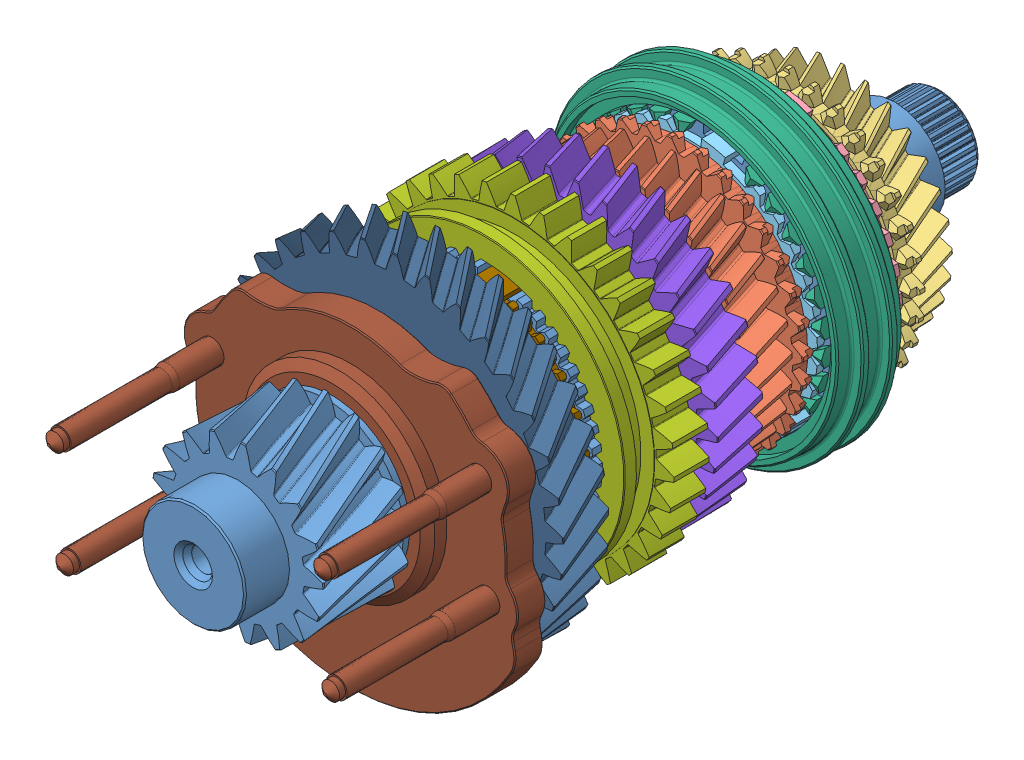
SolidWorks assembly lock3, configuration Default. Lengths in mm.
Overall size (149.64 149.67 253.48).
12 component instances, 11 part files, 28 mates.
Components (placement in the parent):
- Part1 - Copy-1: Part1 - Copy [Default] at (-9.0719 9.4939 -127.4378) size (88.21 88.13 251.48)
- 3rd Gear-1: 3rd Gear [Default] at (-9.0719 9.4939 -34.8178) x (0.981754 -0.190153 0) z (0.190153 0.981754 0) size (89.95 22.5 89.85)
- 4th-1: 4th [Default] at (-9.0719 9.4939 -94.2778) x (1 0 0) z (0 1 0) size (89.95 21.35 89.85)
- 4th Mesh - Copy-1: 4th Mesh - Copy [Default] at (-9.0719 9.4939 -71.9278) x (0.985045 0.172299 0) z (-0.172299 0.985045 0) size (86.29 9.5 85.96)
- gear3 mesh-1: gear3 mesh [Default] at (-9.0719 9.4939 -45.7778) x (0.307677 0.951491 0) z (-0.951491 0.307677 0) size (86.48 9.6 86.41)
- Part3-1: Part3 [Default] at (-9.0719 9.4939 -43.5517) x (0.888761 -0.458371 0) z (-0.458371 -0.888761 0) size (106.2 22 106.2)
- reverse-1: reverse [Default] at (-9.0719 9.4939 16.1439) x (0.555504 -0.831514 0) z (0.831514 0.555504 0) size (107.95 22 107.84)
- 2nd gear-1: 2nd gear [Default] at (-9.0719 9.4939 -1.7178) x (-0.913023 -0.407908 0) z (0.407908 -0.913023 0) size (102.15 21.6 102.2)
- reverse mesh-1: reverse mesh [Default] at (-9.0719 9.4939 4.6222) x (0.487458 -0.873146 0) z (0.873146 0.487458 0) size (80 8.5 80)
- reverse mesh-2: reverse mesh [Default] at (-9.0719 9.4939 32.2222) x (-0.788428 -0.615126 0) z (-0.615126 0.788428 0) size (80 8.5 80)
- 1st gear-1: 1st gear [Default] at (-9.0719 9.4939 41.2222) x (0.996072 -0.088542 0) z (-0.088542 -0.996072 0) size (115.11 23.6 115.04)
- base-1: base [Default] at (-9.0719 9.4939 61.5422) x (-0.996102 -0.088213 0) z (-0.088213 0.996102 0) size (110 64.6 106)
Mates (geometry in assembly coordinates):
- Concentric1: concentric aligned: cylinder of Part1 - Copy-1 through (-9.0719 9.4939 59.5422) axis (0 0 -1) radius 24; cylinder of 3rd Gear-1 through (-9.0719 9.4939 -19.1177) axis (0 0 -1) radius 24
- Lock1: lock: unknown of Part1 - Copy-1; unknown of 3rd Gear-1
- Concentric2: concentric aligned: cylinder of Part1 - Copy-1 through (-9.0719 9.4939 59.5422) axis (0 0 -1) radius 24; cylinder of 4th-1 through (-9.0719 9.4939 -73.0277) axis (0 0 -1) radius 24
- Coincident1: coincident aligned: plane of Part1 - Copy-1 through (-9.0719 9.4939 -94.2778) normal (0 0 -1); plane of 4th-1 through (-9.0719 9.4939 -94.2778) normal (0 0 -1)
- Concentric3: concentric aligned: cylinder of Part1 - Copy-1 through (-9.0719 9.4939 -94.2778) axis (0 0 -1) radius 17; cylinder of 4th Mesh - Copy-1 through (-9.0719 9.4939 -62.4278) axis (0 0 -1) radius 24
- Distance1: distance = 1 mm anti-aligned: plane of 4th Mesh - Copy-1 through (-9.0719 9.4939 -69.2778) normal (0 0 1); plane of Part1 - Copy-1 through (-9.0719 9.4939 -68.2778) normal (0 0 -1)
- Concentric4: concentric aligned: cylinder of Part1 - Copy-1 through (-9.0719 9.4939 59.5422) axis (0 0 -1) radius 24; cylinder of gear3 mesh-1 through (-9.0719 9.4939 -35.7778) axis (0 0 -1) radius 24
- Distance2: distance = 1 mm anti-aligned: plane of gear3 mesh-1 through (-9.0719 9.4939 -45.7778) normal (0 0 -1); plane of Part1 - Copy-1 through (-9.0719 9.4939 -46.7778) normal (0 0 1)
- Concentric5: concentric anti-aligned: cylinder of Part1 - Copy-1 through (-9.0719 9.4939 59.5422) axis (0 0 -1) radius 24; cylinder of Part3-1 through (-9.0719 9.4939 -188.902) axis (0 0 1) radius 44.115
- Parallel1: parallel anti-aligned: plane of Part1 - Copy-1 through (10.643 45.5071 -68.2778) normal (-0.483639 0.875268 0); plane of Part3-1 through (13.7756 47.2314 -36.7966) normal (0.483639 -0.875268 0)
- Concentric6: concentric aligned: cylinder of Part1 - Copy-1 through (-9.0719 9.4939 59.5422) axis (0 0 -1) radius 24; cylinder of reverse-1 through (-9.0719 9.4939 26.1439) axis (0 0 -1) radius 40
- LimitAngle1: limit planar angle = 0.083619 rad aligned: line of 4th Mesh - Copy-1 through (25.78 -16.2142 -71.9278) axis (-0.804751 0.593613 0); line of Part1 - Copy-1 through (28.4032 -13.5815 -68.2778) axis (-0.851518 0.524325 0)
- LimitAngle2: limit planar angle = 0.068648 rad aligned: line of gear3 mesh-1 through (23.9988 -14.1441 -43.1178) axis (0.813547 -0.581499 0); line of Part1 - Copy-1 through (25.8885 -12.0331 -46.7778) axis (0.851518 -0.524325 0)
- LimitDistance1: limit distance = 12.226 mm aligned: plane of 4th-1 through (-9.0719 9.4939 -77.7778) normal (0 0 -1); plane of Part3-1 through (-9.0719 9.4939 -65.5517) normal (0 0 -1)
- Parallel2: parallel anti-aligned: plane of Part1 - Copy-1 through (14.4776 -22.8391 2.2236) normal (-0.444446 -0.895805 0); plane of reverse-1 through (14.4751 -22.841 29.9488) normal (0.444446 0.895805 0)
- Concentric7: concentric anti-aligned: cylinder of Part1 - Copy-1 through (-9.0719 9.4939 59.5422) axis (0 0 -1) radius 24; cylinder of 2nd gear-1 through (-9.0719 9.4939 -17.3178) axis (0 0 1) radius 24
- Distance3: distance = 2 mm anti-aligned: plane of 3rd Gear-1 through (-9.0719 9.4939 -19.2178) normal (0 0 1); plane of 2nd gear-1 through (-9.0719 9.4939 -17.2178) normal (0 0 -1)
- Concentric9: concentric aligned: cylinder of Part1 - Copy-1 through (-9.0719 9.4939 79.0422) axis (0 0 -1) radius 26; cylinder of reverse mesh-1 through (-9.0719 9.4939 14.6222) axis (0 0 -1) radius 24
- Distance4: distance = 0.1 mm anti-aligned: plane of reverse mesh-1 through (-9.0719 9.4939 7.1222) normal (0 0 1); plane of Part1 - Copy-1 through (-9.0719 9.4939 7.2222) normal (0 0 -1)
- Concentric11: concentric anti-aligned: cylinder of Part1 - Copy-1 through (-9.0719 9.4939 79.0422) axis (0 0 -1) radius 26; cylinder of reverse mesh-2 through (-9.0719 9.4939 22.2222) axis (0 0 1) radius 24
- Distance5: distance = 0.5 mm anti-aligned: plane of reverse mesh-2 through (-9.0719 9.4939 29.7222) normal (0 0 -1); plane of Part1 - Copy-1 through (-9.0719 9.4939 29.2222) normal (0 0 1)
- LimitDistance2: limit distance = 3.8617 mm aligned: plane of reverse-1 through (-9.0719 9.4939 4.1439) normal (0 0 -1); plane of 2nd gear-1 through (-9.0719 9.4939 0.2822) normal (0 0 -1)
- LimitAngle3: limit planar angle = 0.068187 rad aligned: line of reverse mesh-1 through (23.5577 -13.6429 4.6222) axis (-0.81574 0.578419 0); line of Part1 - Copy-1 through (24.8876 -11.2616 7.2222) axis (-0.853255 0.521494 0)
- LimitAngle6: limit planar angle = 1.001412 rad aligned: line of reverse mesh-2 through (-43.2423 -7.1309 32.2222) axis (-0.899221 -0.437495 0); line of Part1 - Copy-1 through (25.0583 -11.3659 29.2222) axis (-0.853255 0.521494 0)
- Concentric12: concentric anti-aligned: cylinder of Part1 - Copy-1 through (-9.0719 9.4939 59.5422) axis (0 0 -1) radius 24; cylinder of 1st gear-1 through (-9.0719 9.4939 0.7222) axis (0 0 1) radius 24
- Distance6: distance = 1 mm anti-aligned: plane of 1st gear-1 through (-9.0719 9.4939 33.2222) normal (0 0 -1); plane of reverse mesh-2 through (-9.0719 9.4939 32.2222) normal (0 0 1)
- Concentric13: concentric anti-aligned: cylinder of Part1 - Copy-1 through (-9.0719 9.4939 79.0422) axis (0 0 -1) radius 26; cylinder of base-1 through (-9.0719 9.4939 50.0422) axis (0 0 1) radius 26
- Coincident3: coincident aligned: plane of Part1 - Copy-1 through (-9.0719 9.4939 61.5422) normal (0 0 -1); plane of base-1 through (-64.1376 -21.1875 61.5422) normal (0 0 -1)
